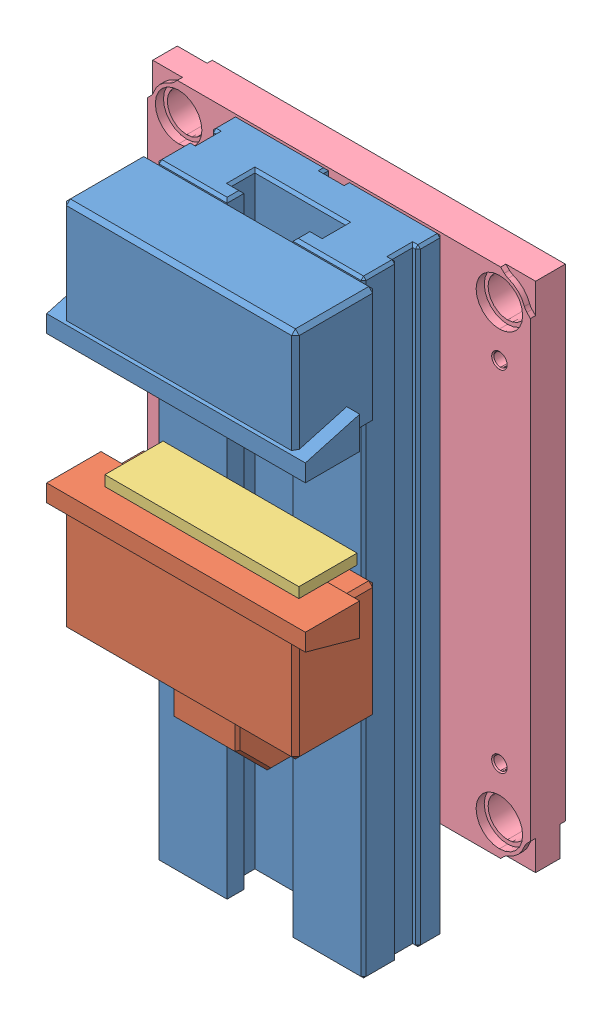
SolidWorks assembly ETAU SAGOP GRAND, configuration Défaut. Lengths in mm.
Overall size (296 470 153).
5 component instances, 4 part files, 15 mates.
Components (placement in the parent):
- Copie de ETAU SAGOP 200 FIXE_1^ETAU SAGOP GRAND-1: Copie de ETAU SAGOP 200 FIXE_1^ETAU SAGOP GRAND [Défaut] at (0 -136 537) x (0 -1 0) z (0 0 1) size (470 200 126) (virtual)
- Copie de ETAU SAGOP 200 MOBILE_1^ETAU SAGOP GRAND-1: Copie de ETAU SAGOP 200 MOBILE_1^ETAU SAGOP GRAND [Défaut] at (0 -186 537) x (0 -1 0) z (0 0 1) size (154 200 96) (virtual)
- Copie de CALE_1^ETAU SAGOP GRAND-3: Copie de CALE_1^ETAU SAGOP GRAND [Défaut] at (75 -4 83.5) x (0 -1 0) z (-1 0 0) size (8 45 150) (virtual)
- Copie de CALE_1^ETAU SAGOP GRAND-4: Copie de CALE_1^ETAU SAGOP GRAND [Défaut] at (75 -96 83.5) x (0 -1 0) z (-1 0 0) size (8 45 150) (virtual)
- Copie de F_50_296396_27_1^ETAU SAGOP GRAND-1: Copie de F_50_296396_27_1^ETAU SAGOP GRAND [Défaut] at (0 -104 0) x (0 -1 0) z (0 0 1) size (396 296 27) (virtual)
Mates (geometry in assembly coordinates):
- Coïncidente1: coincident: plane of Copie de ETAU SAGOP 200 FIXE_1^ETAU SAGOP GRAND-1 through (-90 0 123.7) normal (0 -1 0); plane of assembly through (0 0 0) normal (0 1 0)
- Coïncidente2: coincident: plane of Copie de ETAU SAGOP 200 FIXE_1^ETAU SAGOP GRAND-1 through (-8 94 0) normal (0 0 -1); plane of assembly through (0 0 0) normal (0 0 1)
- Distance1: distance = 100 mm: plane of assembly through (0 0 0) normal (1 0 0); plane of Copie de ETAU SAGOP 200 FIXE_1^ETAU SAGOP GRAND-1 through (-100 13.3333 126) normal (-1 0 0)
- Coïncidente4: coincident: plane of Copie de ETAU SAGOP 200 FIXE_1^ETAU SAGOP GRAND-1 through (25.5 94 61) normal (0 0 1); plane of Copie de ETAU SAGOP 200 MOBILE_1^ETAU SAGOP GRAND-1 through (-90 -100 61) normal (0 0 -1)
- Coïncidente5: coincident: plane of Copie de ETAU SAGOP 200 FIXE_1^ETAU SAGOP GRAND-1 through (-25.5 94 61) normal (1 0 0); plane of Copie de ETAU SAGOP 200 MOBILE_1^ETAU SAGOP GRAND-1 through (-25.5 -254 30) normal (-1 0 0)
- Distance2: distance = 100 mm: plane of Copie de ETAU SAGOP 200 FIXE_1^ETAU SAGOP GRAND-1 through (-90 0 123.7) normal (0 -1 0); plane of Copie de ETAU SAGOP 200 MOBILE_1^ETAU SAGOP GRAND-1 through (90 -100 123.7) normal (0 1 0)
- Coïncidente14: coincident: plane of Copie de CALE_1^ETAU SAGOP GRAND-3 through (-75 -8 61) normal (0 0 -1); plane of Copie de CALE_1^ETAU SAGOP GRAND-4 through (-75 -100 61) normal (0 0 -1)
- Coïncidente15: coincident: plane of Copie de CALE_1^ETAU SAGOP GRAND-3 through (0 -4 83.5) normal (-1 0 0); plane of Copie de CALE_1^ETAU SAGOP GRAND-4 through (0 -96 83.5) normal (-1 0 0)
- Coïncidente16: coincident: plane of Copie de ETAU SAGOP 200 FIXE_1^ETAU SAGOP GRAND-1 through (-80 94 61) normal (0 0 1); plane of Copie de CALE_1^ETAU SAGOP GRAND-3 through (-75 -8 61) normal (0 0 -1)
- Coïncidente17: coincident: plane of Copie de ETAU SAGOP 200 FIXE_1^ETAU SAGOP GRAND-1 through (0 -136 537) normal (1 0 0); plane of Copie de CALE_1^ETAU SAGOP GRAND-3 through (0 -4 83.5) normal (-1 0 0)
- Coïncidente18: coincident: plane of Copie de ETAU SAGOP 200 FIXE_1^ETAU SAGOP GRAND-1 through (-90 0 123.7) normal (0 -1 0); plane of Copie de CALE_1^ETAU SAGOP GRAND-3 through (-75 0 61) normal (0 1 0)
- Coïncidente19: coincident: plane of Copie de ETAU SAGOP 200 MOBILE_1^ETAU SAGOP GRAND-1 through (90 -100 123.7) normal (0 1 0); plane of Copie de CALE_1^ETAU SAGOP GRAND-4 through (-75 -100 61) normal (0 -1 0)
- Coïncidente20: coincident: plane of Copie de ETAU SAGOP 200 FIXE_1^ETAU SAGOP GRAND-1 through (-80 94 35) normal (0 1 0); plane of Copie de F_50_296396_27_1^ETAU SAGOP GRAND-1 through (0 94 -13.5) normal (0 1 0)
- Coïncidente21: coincident: plane of Copie de ETAU SAGOP 200 FIXE_1^ETAU SAGOP GRAND-1 through (80 94 0) normal (0 0 -1); plane of Copie de F_50_296396_27_1^ETAU SAGOP GRAND-1 through (0 -104 0) normal (0 0 1)
- Coïncidente22: coincident: plane of Copie de F_50_296396_27_1^ETAU SAGOP GRAND-1 through (0 -104 0) normal (1 0 0); plane of assembly through (0 0 0) normal (1 0 0)
